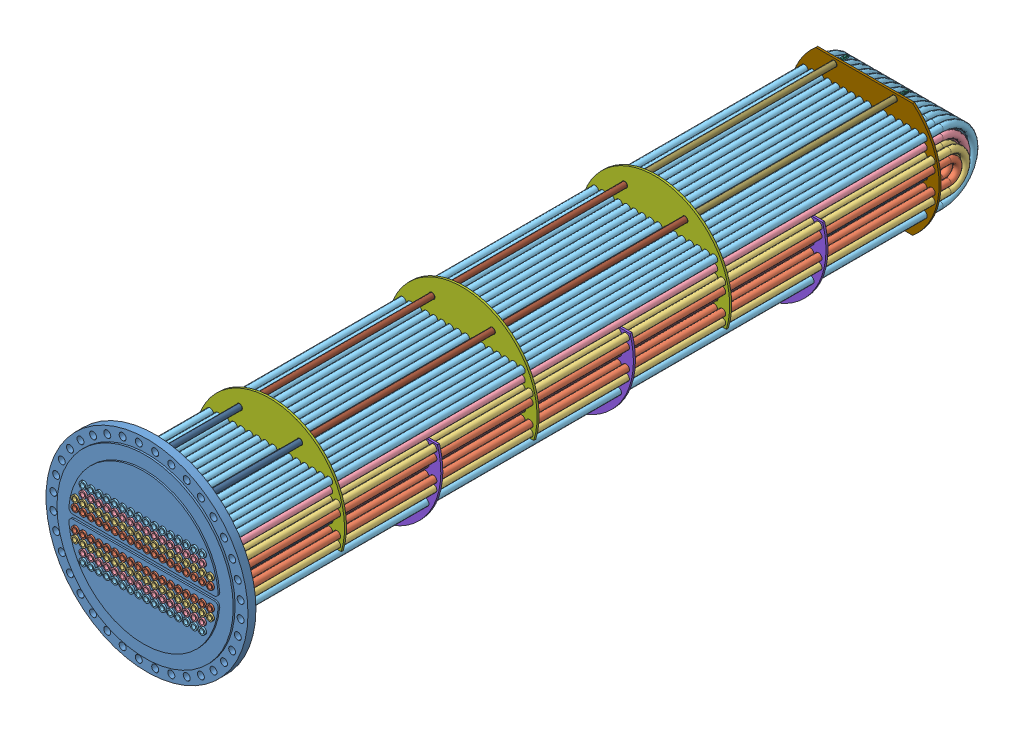
SolidWorks assembly assembly of u tube, configuration Default. Lengths in mm.
Overall size (636 636 2440.65).
118 component instances, 14 part files, 107 mates.
Components (placement in the parent):
- Tubesheet-1: Tubesheet [Default] at (254.3026 327.9932 481.92) x (-1 0 0) z (0 0 -1) size (636 636 47)
- U Tube 0.5 Inch-1: U Tube 0.5 Inch [Default] at (41.8026 327.9932 510.42) size (21.3 81.3 2365.65)
- U Tube 0.5 In x 4844 -1: U Tube 0.5 In x 4844  [Default] at (41.8026 327.9932 510.42) size (21.3 131.3 2390.65)
- U Tube 0.5 Inch-2: U Tube 0.5 Inch [Default] at (66.8026 327.9932 510.42) size (21.3 81.3 2365.65)
- U Tube 0.5 Inch-3: U Tube 0.5 Inch [Default] at (91.8026 327.9932 510.42) size (21.3 81.3 2365.65)
- U Tube 0.5 Inch-4: U Tube 0.5 Inch [Default] at (116.8026 327.9932 510.42) size (21.3 81.3 2365.65)
- U Tube 0.5 Inch-5: U Tube 0.5 Inch [Default] at (141.8026 327.9932 510.42) size (21.3 81.3 2365.65)
- U Tube 0.5 Inch-6: U Tube 0.5 Inch [Default] at (166.8026 327.9932 510.42) size (21.3 81.3 2365.65)
- U Tube 0.5 Inch-7: U Tube 0.5 Inch [Default] at (191.8026 327.9932 510.42) size (21.3 81.3 2365.65)
- U Tube 0.5 Inch-8: U Tube 0.5 Inch [Default] at (216.8026 327.9932 510.42) size (21.3 81.3 2365.65)
- U Tube 0.5 Inch-9: U Tube 0.5 Inch [Default] at (241.8026 327.9932 510.42) size (21.3 81.3 2365.65)
- U Tube 0.5 Inch-10: U Tube 0.5 Inch [Default] at (266.8026 327.9932 510.42) size (21.3 81.3 2365.65)
- U Tube 0.5 Inch-11: U Tube 0.5 Inch [Default] at (291.8026 327.9932 510.42) size (21.3 81.3 2365.65)
- U Tube 0.5 Inch-12: U Tube 0.5 Inch [Default] at (316.8026 327.9932 510.42) size (21.3 81.3 2365.65)
- U Tube 0.5 Inch-13: U Tube 0.5 Inch [Default] at (341.8026 327.9932 510.42) size (21.3 81.3 2365.65)
- U Tube 0.5 Inch-14: U Tube 0.5 Inch [Default] at (366.8026 327.9932 510.42) size (21.3 81.3 2365.65)
- U Tube 0.5 Inch-15: U Tube 0.5 Inch [Default] at (391.8026 327.9932 510.42) size (21.3 81.3 2365.65)
- U Tube 0.5 Inch-16: U Tube 0.5 Inch [Default] at (416.8026 327.9932 510.42) size (21.3 81.3 2365.65)
- U Tube 0.5 Inch-17: U Tube 0.5 Inch [Default] at (441.8026 327.9932 510.42) size (21.3 81.3 2365.65)
- U Tube 0.5 Inch-18: U Tube 0.5 Inch [Default] at (466.8026 327.9932 510.42) size (21.3 81.3 2365.65)
- U Tube 0.5 In x 4844 -2: U Tube 0.5 In x 4844  [Default] at (66.8026 327.9932 510.42) size (21.3 131.3 2390.65)
- U Tube 0.5 In x 4844 -3: U Tube 0.5 In x 4844  [Default] at (91.8026 327.9932 510.42) size (21.3 131.3 2390.65)
- U Tube 0.5 In x 4844 -4: U Tube 0.5 In x 4844  [Default] at (116.8026 327.9932 510.42) size (21.3 131.3 2390.65)
- U Tube 0.5 In x 4844 -5: U Tube 0.5 In x 4844  [Default] at (141.8026 327.9932 510.42) size (21.3 131.3 2390.65)
- U Tube 0.5 In x 4844 -6: U Tube 0.5 In x 4844  [Default] at (166.8026 327.9932 510.42) size (21.3 131.3 2390.65)
- U Tube 0.5 In x 4844 -7: U Tube 0.5 In x 4844  [Default] at (191.8026 327.9932 510.42) size (21.3 131.3 2390.65)
- U Tube 0.5 In x 4844 -8: U Tube 0.5 In x 4844  [Default] at (216.8026 327.9932 510.42) size (21.3 131.3 2390.65)
- U Tube 0.5 In x 4844 -9: U Tube 0.5 In x 4844  [Default] at (241.8026 327.9932 510.42) size (21.3 131.3 2390.65)
- U Tube 0.5 In x 4844 -10: U Tube 0.5 In x 4844  [Default] at (266.8026 327.9932 510.42) size (21.3 131.3 2390.65)
- U Tube 0.5 In x 4844 -11: U Tube 0.5 In x 4844  [Default] at (291.8026 327.9932 510.42) size (21.3 131.3 2390.65)
- U Tube 0.5 In x 4844 -12: U Tube 0.5 In x 4844  [Default] at (316.8026 327.9932 510.42) size (21.3 131.3 2390.65)
- U Tube 0.5 In x 4844 -13: U Tube 0.5 In x 4844  [Default] at (341.8026 327.9932 510.42) size (21.3 131.3 2390.65)
- U Tube 0.5 In x 4844 -14: U Tube 0.5 In x 4844  [Default] at (366.8026 327.9932 510.42) size (21.3 131.3 2390.65)
- U Tube 0.5 In x 4844 -15: U Tube 0.5 In x 4844  [Default] at (391.8026 327.9932 510.42) size (21.3 131.3 2390.65)
- U Tube 0.5 In x 4844 -16: U Tube 0.5 In x 4844  [Default] at (416.8026 327.9932 510.42) size (21.3 131.3 2390.65)
- U Tube 0.5 In x 4844 -17: U Tube 0.5 In x 4844  [Default] at (441.8026 327.9932 510.42) size (21.3 131.3 2390.65)
- U Tube 0.5 In x 4844 -18: U Tube 0.5 In x 4844  [Default] at (466.8026 327.9932 510.42) size (21.3 131.3 2390.65)
- U Tube 0.5 In x 4923 -1: U Tube 0.5 In x 4923  [Default] at (66.8026 327.9932 510.42) size (21.3 181.3 2415.65)
- U Tube 0.5 In x 5000 -1: U Tube 0.5 In x 5000  [Default] at (66.8026 327.9932 510.42) size (21.3 231.3 2440.65)
- U Tube 0.5 In x 5000 -2: U Tube 0.5 In x 5000  [Default] at (91.8026 327.9932 510.42) size (21.3 231.3 2440.65)
- U Tube 0.5 In x 5000 -3: U Tube 0.5 In x 5000  [Default] at (116.8026 327.9932 510.42) size (21.3 231.3 2440.65)
- U Tube 0.5 In x 5000 -4: U Tube 0.5 In x 5000  [Default] at (141.8026 327.9932 510.42) size (21.3 231.3 2440.65)
- U Tube 0.5 In x 5000 -5: U Tube 0.5 In x 5000  [Default] at (166.8026 327.9932 510.42) size (21.3 231.3 2440.65)
- U Tube 0.5 In x 5000 -6: U Tube 0.5 In x 5000  [Default] at (191.8026 327.9932 510.42) size (21.3 231.3 2440.65)
- U Tube 0.5 In x 5000 -7: U Tube 0.5 In x 5000  [Default] at (216.8026 327.9932 510.42) size (21.3 231.3 2440.65)
- U Tube 0.5 In x 5000 -8: U Tube 0.5 In x 5000  [Default] at (241.8026 327.9932 510.42) size (21.3 231.3 2440.65)
- U Tube 0.5 In x 5000 -9: U Tube 0.5 In x 5000  [Default] at (266.8026 327.9932 510.42) size (21.3 231.3 2440.65)
- U Tube 0.5 In x 5000 -10: U Tube 0.5 In x 5000  [Default] at (291.8026 327.9932 510.42) size (21.3 231.3 2440.65)
- U Tube 0.5 In x 5000 -11: U Tube 0.5 In x 5000  [Default] at (316.8026 327.9932 510.42) size (21.3 231.3 2440.65)
- U Tube 0.5 In x 5000 -12: U Tube 0.5 In x 5000  [Default] at (341.8026 327.9932 510.42) size (21.3 231.3 2440.65)
- U Tube 0.5 In x 5000 -13: U Tube 0.5 In x 5000  [Default] at (366.8026 327.9932 510.42) size (21.3 231.3 2440.65)
- U Tube 0.5 In x 5000 -14: U Tube 0.5 In x 5000  [Default] at (391.8026 327.9932 510.42) size (21.3 231.3 2440.65)
- U Tube 0.5 In x 5000 -15: U Tube 0.5 In x 5000  [Default] at (416.8026 327.9932 510.42) size (21.3 231.3 2440.65)
- U Tube 0.5 In x 5000 -16: U Tube 0.5 In x 5000  [Default] at (441.8026 327.9932 510.42) size (21.3 231.3 2440.65)
- U Tube 0.5 In x 4923 -2: U Tube 0.5 In x 4923  [Default] at (91.8026 327.9932 510.42) size (21.3 181.3 2415.65)
- U Tube 0.5 In x 4923 -3: U Tube 0.5 In x 4923  [Default] at (116.8026 327.9932 510.42) size (21.3 181.3 2415.65)
- U Tube 0.5 In x 4923 -4: U Tube 0.5 In x 4923  [Default] at (141.8026 327.9932 510.42) size (21.3 181.3 2415.65)
- U Tube 0.5 In x 4923 -5: U Tube 0.5 In x 4923  [Default] at (166.8026 327.9932 510.42) size (21.3 181.3 2415.65)
- U Tube 0.5 In x 4923 -6: U Tube 0.5 In x 4923  [Default] at (191.8026 327.9932 510.42) size (21.3 181.3 2415.65)
- U Tube 0.5 In x 4923 -7: U Tube 0.5 In x 4923  [Default] at (216.8026 327.9932 510.42) size (21.3 181.3 2415.65)
- U Tube 0.5 In x 4923 -8: U Tube 0.5 In x 4923  [Default] at (241.8026 327.9932 510.42) size (21.3 181.3 2415.65)
- U Tube 0.5 In x 4923 -9: U Tube 0.5 In x 4923  [Default] at (266.8026 327.9932 510.42) size (21.3 181.3 2415.65)
- U Tube 0.5 In x 4923 -10: U Tube 0.5 In x 4923  [Default] at (291.8026 327.9932 510.42) size (21.3 181.3 2415.65)
- U Tube 0.5 In x 4923 -11: U Tube 0.5 In x 4923  [Default] at (316.8026 327.9932 510.42) size (21.3 181.3 2415.65)
- U Tube 0.5 In x 4923 -12: U Tube 0.5 In x 4923  [Default] at (341.8026 327.9932 510.42) size (21.3 181.3 2415.65)
- U Tube 0.5 In x 4923 -13: U Tube 0.5 In x 4923  [Default] at (366.8026 327.9932 510.42) size (21.3 181.3 2415.65)
- U Tube 0.5 In x 4923 -14: U Tube 0.5 In x 4923  [Default] at (391.8026 327.9932 510.42) size (21.3 181.3 2415.65)
- U Tube 0.5 In x 4923 -15: U Tube 0.5 In x 4923  [Default] at (416.8026 327.9932 510.42) size (21.3 181.3 2415.65)
- U Tube 0.5 In x 4923 -16: U Tube 0.5 In x 4923  [Default] at (441.8026 327.9932 510.42) size (21.3 181.3 2415.65)
- Tie Road-1: Tie Road [Default] at (349.3026 163.4484 -666.58) size (9.99 9.59 2280.98)
- Plate spacer 2-1: Plate spacer 2 [Default] at (254.8433 328.9394 105.245) size (472 306 6.35)
- Plate spacer-1: Plate spacer [Default] at (253.7619 327.047 -197.935) x (-1 0 0) z (0 0 1) size (472 306 6.35)
- Plate spacer 2-2: Plate spacer 2 [Default] at (254.8433 328.9394 -501.105) size (472 306 6.35)
- Plate spacer 2-3: Plate spacer 2 [Default] at (254.8433 328.9394 -1107.455) size (472 306 6.35)
- Plate spacer-2: Plate spacer [Default] at (253.7619 327.047 -804.285) x (-1 0 0) z (0 0 1) size (472 306 6.35)
- Plate spacer-3: Plate spacer [Default] at (253.7619 327.047 -1410.635) x (-1 0 0) z (0 0 1) size (472 306 6.35)
- Plate Spacer 3-1: Plate Spacer 3 [Default] at (252.2845 352.0761 -1766.985) size (472 360 6.35)
- Tie Road-2: Tie Road [Default] at (159.3026 163.4484 -666.58) x (0.5 -0.866025 0) z (0 0 1) size (9.99 9.59 2280.98)
- Tie Road-3: Tie Road [Default] at (64.3026 327.9932 -666.58) x (-0.5 -0.866025 0) z (0 0 1) size (9.99 9.59 2280.98)
- Tie Road-4: Tie Road [Default] at (159.3026 492.538 -666.58) x (-1 0 0) z (0 0 1) size (9.99 9.59 2280.98)
- Tie Road-5: Tie Road [Default] at (349.3026 492.538 -666.58) x (-0.5 0.866025 0) z (0 0 1) size (9.99 9.59 2280.98)
- Tie Road-6: Tie Road [Default] at (444.3026 327.9932 -666.58) x (0.5 0.866025 0) z (0 0 1) size (9.99 9.59 2280.98)
- Spacer 2-1: Spacer 2 [Default] at (349.3026 492.538 458.42) size (17.1 17.1 350)
- Spacer 2-2: Spacer 2 [Default] at (444.3026 327.9932 458.42) x (0.987351 0.158553 0) z (0 0 1) size (17.1 17.1 350)
- Spacer 2-4: Spacer 2 [Default] at (159.3026 492.538 458.42) x (0.959125 0.282984 0) z (0 0 1) size (17.1 17.1 350)
- Spacer 2-6: Spacer 2 [Default] at (64.3026 327.9932 458.42) x (0.928571 0.371154 0) z (0 0 1) size (17.1 17.1 350)
- Spacer 2-8: Spacer 2 [Default] at (159.3026 163.4484 -1413.81) x (0.906989 0.421154 0) z (0 0 1) size (17.1 17.1 350)
- Spacer 2-10: Spacer 2 [Default] at (349.3026 163.4484 -1413.81) x (0.902849 0.429957 0) z (0 0 1) size (17.1 17.1 350)
- Spacer 2-12: Spacer 2 [Default] at (444.3026 327.9932 -1413.81) x (0.919615 0.39282 0) z (0 0 1) size (17.1 17.1 350)
- Spacer 2-14: Spacer 2 [Default] at (64.3026 327.9932 -1413.81) x (0.952324 0.305088 0) z (0 0 1) size (17.1 17.1 350)
- Spacer 3-1: Spacer 3 [Default] at (159.3026 492.538 102.07) x (0.396884 -0.917869 0) z (0 0 1) size (17.1 17.1 600)
- Spacer 3-2: Spacer 3 [Default] at (349.3026 492.538 102.07) x (0.537395 -0.843331 0) z (0 0 1) size (17.1 17.1 600)
- Spacer 3-4: Spacer 3 [Default] at (159.3026 492.538 -504.28) x (0.640403 -0.768039 0) z (0 0 1) size (17.1 17.1 600)
- Spacer 3-6: Spacer 3 [Default] at (349.3026 492.538 -504.28) x (0.709206 -0.705001 0) z (0 0 1) size (17.1 17.1 600)
- Spacer 3-8: Spacer 3 [Default] at (159.3026 163.4484 -201.11) x (0.746534 -0.665348 0) z (0 0 1) size (17.1 17.1 600)
- Spacer 3-10: Spacer 3 [Default] at (349.3026 163.4484 -201.11) x (0.752971 -0.658054 0) z (0 0 1) size (17.1 17.1 600)
- Spacer 3-12: Spacer 3 [Default] at (349.3026 163.4484 -807.46) x (0.725538 -0.688182 0) z (0 0 1) size (17.1 17.1 600)
- Spacer 3-14: Spacer 3 [Default] at (159.3026 163.4484 -807.46) x (0.657993 -0.753024 0) z (0 0 1) size (17.1 17.1 600)
- Spacer 4-1: Spacer 4 [Default] at (349.3026 163.4484 458.415) x (-0.656947 -0.753937 0) z (0 0 1) size (17.1 17.1 653.17)
- Spacer 4-2: Spacer 4 [Default] at (159.3026 163.4484 458.415) x (-0.529098 -0.848561 0) z (0 0 1) size (17.1 17.1 653.17)
- Spacer 4-4: Spacer 4 [Default] at (349.3026 492.538 -1110.635) x (-0.416742 -0.909025 0) z (0 0 1) size (17.1 17.1 653.17)
- Spacer 4-6: Spacer 4 [Default] at (159.3026 492.538 -1110.635) x (-0.330196 -0.943912 0) z (0 0 1) size (17.1 17.1 653.17)
- Spacer 1-1: Spacer 1 [Default] at (444.3026 327.9932 102.08) x (0.766722 -0.641979 0) z (0 0 1) size (17.1 17.1 296.85)
- Spacer 1-2: Spacer 1 [Default] at (444.3026 327.9932 -201.095) x (0.858811 -0.512293 0) z (0 0 1) size (17.1 17.1 296.85)
- Spacer 1-4: Spacer 1 [Default] at (444.3026 327.9932 -504.27) x (0.917052 -0.398768 0) z (0 0 1) size (17.1 17.1 296.85)
- Spacer 1-6: Spacer 1 [Default] at (444.3026 327.9932 -807.445) x (0.950229 -0.311552 0) z (0 0 1) size (17.1 17.1 296.85)
- Spacer 1-8: Spacer 1 [Default] at (444.3026 327.9932 -1110.62) x (0.965781 -0.259361 0) z (0 0 1) size (17.1 17.1 296.85)
- Spacer 1-10: Spacer 1 [Default] at (64.3026 327.9932 -1110.62) x (0.968258 -0.249953 0) z (0 0 1) size (17.1 17.1 296.85)
- Spacer 1-12: Spacer 1 [Default] at (64.3026 327.9932 -504.27) x (0.957272 -0.28919 0) z (0 0 1) size (17.1 17.1 296.85)
- Spacer 1-14: Spacer 1 [Default] at (64.3026 327.9932 -807.445) x (0.926028 -0.377455 0) z (0 0 1) size (17.1 17.1 296.85)
- Spacer 1-16: Spacer 1 [Default] at (64.3026 327.9932 -201.095) x (0.863946 -0.503584 0) z (0 0 1) size (17.1 17.1 296.85)
- Spacer 1-18: Spacer 1 [Default] at (64.3026 327.9932 102.08) x (0.932862 -0.360233 0) z (0 0 1) size (17.1 17.1 296.85)
- hex flange nut gradea_iso-1: hex flange nut gradea_iso [ISO - 4161 - M10 - N] at (159.3026 492.538 -1780.16) x (0.923728 0.383049 0) z (0 0 -1) size (21.8 21.8 10)
- hex flange nut gradea_iso-2: hex flange nut gradea_iso [ISO - 4161 - M10 - N] at (349.3026 492.538 -1780.16) x (0.923728 0.383049 0) z (0 0 -1) size (21.8 21.8 10)
- hex flange nut gradea_iso-3: hex flange nut gradea_iso [ISO - 4161 - M10 - N] at (444.2942 327.9932 -1780.16) x (0.923728 0.383049 0) z (0 0 -1) size (21.8 21.8 10)
- hex flange nut gradea_iso-4: hex flange nut gradea_iso [ISO - 4161 - M10 - N] at (349.3026 163.4484 -1780.16) x (0.923728 0.383049 0) z (0 0 -1) size (21.8 21.8 10)
- hex flange nut gradea_iso-5: hex flange nut gradea_iso [ISO - 4161 - M10 - N] at (159.3026 163.4484 -1780.16) x (0.923728 0.383049 0) z (0 0 -1) size (21.8 21.8 10)
- hex flange nut gradea_iso-6: hex flange nut gradea_iso [ISO - 4161 - M10 - N] at (65.3924 327.9932 -1780.16) x (0.923728 0.383049 0) z (0 0 -1) size (21.8 21.8 10)
Mates (geometry in assembly coordinates):
- Concentric1: concentric aligned: cylinder of Tubesheet-1 through (41.8026 357.9932 505.421) axis (0 0 -1) radius 11; cylinder of U Tube 0.5 Inch-1 through (41.8026 357.9932 510.42) axis (0 0 -1) radius 10.65
- Concentric2: concentric anti-aligned: cylinder of Tubesheet-1 through (41.8026 297.9932 505.421) axis (0 0 -1) radius 11; cylinder of U Tube 0.5 Inch-1 through (41.8026 297.9932 -1814.58) axis (0 0 1) radius 10.65
- Distance1: distance = 5 mm aligned: plane of Tubesheet-1 through (32.1568 347.4932 505.42) normal (0 0 1); plane of U Tube 0.5 Inch-1 through (41.8026 357.9932 510.42) normal (0 0 1)
- Concentric3: concentric aligned: cylinder of Tubesheet-1 through (41.8026 382.9932 505.421) axis (0 0 -1) radius 11; cylinder of U Tube 0.5 In x 4844 -1 through (41.8026 382.9932 510.42) axis (0 0 -1) radius 10.65
- Concentric4: concentric anti-aligned: cylinder of Tubesheet-1 through (41.8026 272.9932 505.421) axis (0 0 -1) radius 11; cylinder of U Tube 0.5 In x 4844 -1 through (41.8026 272.9932 -1814.58) axis (0 0 1) radius 10.65
- Distance2: distance = 5 mm aligned: plane of U Tube 0.5 In x 4844 -1 through (41.8026 382.9932 510.42) normal (0 0 1); plane of Tubesheet-1 through (32.1568 347.4932 505.42) normal (0 0 1)
- Concentric5: concentric aligned: cylinder of Tubesheet-1 through (66.8026 407.9932 505.421) axis (0 0 -1) radius 11; cylinder of U Tube 0.5 In x 4923 -1 through (66.8026 407.9932 510.42) axis (0 0 -1) radius 10.65
- Concentric6: concentric anti-aligned: cylinder of Tubesheet-1 through (66.8026 247.9932 505.421) axis (0 0 -1) radius 11; cylinder of U Tube 0.5 In x 4923 -1 through (66.8026 247.9932 -1814.58) axis (0 0 1) radius 10.65
- Distance3: distance = 5 mm aligned: plane of Tubesheet-1 through (32.1568 347.4932 505.42) normal (0 0 1); plane of U Tube 0.5 In x 4923 -1 through (66.8026 407.9932 510.42) normal (0 0 1)
- Concentric7: concentric aligned: cylinder of Tubesheet-1 through (66.8026 432.9932 505.421) axis (0 0 -1) radius 11; cylinder of U Tube 0.5 In x 5000 -1 through (66.8026 432.9932 510.42) axis (0 0 -1) radius 10.65
- Distance4: distance = 5 mm aligned: plane of Tubesheet-1 through (32.1568 347.4932 505.42) normal (0 0 1); plane of U Tube 0.5 In x 5000 -1 through (66.8026 432.9932 510.42) normal (0 0 1)
- Concentric8: concentric anti-aligned: cylinder of Tubesheet-1 through (66.8026 222.9932 505.421) axis (0 0 -1) radius 11; cylinder of U Tube 0.5 In x 5000 -1 through (66.8026 222.9932 -1814.58) axis (0 0 1) radius 10.65
- Distance5: distance = 15 mm anti-aligned: plane of Tubesheet-1 through (254.3026 327.9932 458.42) normal (0 0 -1); plane of Tie Road-1 through (349.3026 163.4484 473.42) normal (0 0 1)
- Concentric9: concentric anti-aligned: cone of Tubesheet-1 through (349.3026 163.4484 458.8063) axis (0 0 1); cylinder of Tie Road-1 through (349.3026 163.4484 473.42) axis (0 0 -1) radius 4.7625
- Concentric10: concentric aligned: cylinder of U Tube 0.5 Inch-1 through (41.8026 357.9932 510.42) axis (0 0 -1) radius 10.65; cylinder of Plate spacer 2-1 through (41.8026 357.9932 108.42) axis (0 0 -1) radius 11
- Concentric11: concentric anti-aligned: cylinder of U Tube 0.5 In x 4844 -1 through (41.8026 272.9932 -1814.58) axis (0 0 1) radius 10.65; cylinder of Plate spacer 2-1 through (41.8026 272.9932 108.42) axis (0 0 -1) radius 11
- Distance6: distance = 350 mm anti-aligned: plane of Tubesheet-1 through (32.1568 347.4932 458.42) normal (0 0 -1); plane of Plate spacer 2-1 through (254.8433 328.9394 108.42) normal (0 0 1)
- Concentric12: concentric aligned: cylinder of U Tube 0.5 In x 4844 -1 through (41.8026 382.9932 510.42) axis (0 0 -1) radius 10.65; cylinder of Plate spacer-1 through (41.8026 382.9932 -194.76) axis (0 0 -1) radius 11
- Concentric13: concentric aligned: cylinder of U Tube 0.5 Inch-1 through (41.8026 357.9932 510.42) axis (0 0 -1) radius 10.65; cylinder of Plate spacer-1 through (41.8026 357.9932 -194.76) axis (0 0 -1) radius 11
- Distance7: distance = 653.18 mm anti-aligned: plane of Tubesheet-1 through (32.1568 347.4932 458.42) normal (0 0 -1); plane of Plate spacer-1 through (253.7619 327.047 -194.76) normal (0 0 1)
- Distance8: distance = 600 mm anti-aligned: plane of Plate spacer 2-1 through (254.8433 328.9394 102.07) normal (0 0 -1); plane of Plate spacer 2-2 through (254.8433 328.9394 -497.93) normal (0 0 1)
- Concentric14: concentric aligned: cylinder of U Tube 0.5 Inch-1 through (41.8026 357.9932 510.42) axis (0 0 -1) radius 10.65; cylinder of Plate spacer 2-2 through (41.8026 357.9932 -497.93) axis (0 0 -1) radius 11
- Concentric15: concentric aligned: cylinder of U Tube 0.5 In x 4844 -1 through (41.8026 382.9932 510.42) axis (0 0 -1) radius 10.65; cylinder of Plate spacer 2-2 through (41.8026 382.9932 -497.93) axis (0 0 -1) radius 11
- Distance9: distance = 600 mm anti-aligned: plane of Plate spacer 2-2 through (254.8433 328.9394 -504.28) normal (0 0 -1); plane of Plate spacer 2-3 through (254.8433 328.9394 -1104.28) normal (0 0 1)
- Concentric16: concentric aligned: cylinder of U Tube 0.5 Inch-1 through (41.8026 357.9932 510.42) axis (0 0 -1) radius 10.65; cylinder of Plate spacer 2-3 through (41.8026 357.9932 -1104.28) axis (0 0 -1) radius 11
- Concentric17: concentric aligned: cylinder of U Tube 0.5 In x 4844 -1 through (41.8026 382.9932 510.42) axis (0 0 -1) radius 10.65; cylinder of Plate spacer 2-3 through (41.8026 382.9932 -1104.28) axis (0 0 -1) radius 11
- Distance10: distance = 600 mm anti-aligned: plane of Plate spacer-1 through (253.7619 327.047 -201.11) normal (0 0 -1); plane of Plate spacer-2 through (253.7619 327.047 -801.11) normal (0 0 1)
- Concentric18: concentric aligned: cylinder of U Tube 0.5 Inch-1 through (41.8026 357.9932 510.42) axis (0 0 -1) radius 10.65; cylinder of Plate spacer-2 through (41.8026 357.9932 -801.11) axis (0 0 -1) radius 11
- Concentric19: concentric aligned: cylinder of U Tube 0.5 In x 4844 -1 through (41.8026 382.9932 510.42) axis (0 0 -1) radius 10.65; cylinder of Plate spacer-2 through (41.8026 382.9932 -801.11) axis (0 0 -1) radius 11
- Distance11: distance = 600 mm anti-aligned: plane of Plate spacer-2 through (253.7619 327.047 -807.46) normal (0 0 -1); plane of Plate spacer-3 through (253.7619 327.047 -1407.46) normal (0 0 1)
- Concentric20: concentric aligned: cylinder of U Tube 0.5 Inch-1 through (41.8026 357.9932 510.42) axis (0 0 -1) radius 10.65; cylinder of Plate spacer-3 through (41.8026 357.9932 -1407.46) axis (0 0 -1) radius 11
- Concentric21: concentric aligned: cylinder of U Tube 0.5 In x 4844 -1 through (41.8026 382.9932 510.42) axis (0 0 -1) radius 10.65; cylinder of Plate spacer-3 through (41.8026 382.9932 -1407.46) axis (0 0 -1) radius 11
- Distance12: distance = 350 mm anti-aligned: plane of Plate Spacer 3-1 through (252.2845 352.0761 -1763.81) normal (0 0 1); plane of Plate spacer-3 through (253.7619 327.047 -1413.81) normal (0 0 -1)
- Concentric22: concentric aligned: cylinder of U Tube 0.5 Inch-1 through (41.8026 357.9932 510.42) axis (0 0 -1) radius 10.65; cylinder of Plate Spacer 3-1 through (41.8026 357.9932 -1763.81) axis (0 0 -1) radius 11
- Concentric23: concentric aligned: cylinder of U Tube 0.5 In x 4844 -1 through (41.8026 382.9932 510.42) axis (0 0 -1) radius 10.65; cylinder of Plate Spacer 3-1 through (41.8026 382.9932 -1763.81) axis (0 0 -1) radius 11
- Concentric24: concentric anti-aligned: cylinder of Tie Road-5 through (349.3026 492.538 473.42) axis (0 0 -1) radius 4.7625; cylinder of Spacer 2-1 through (349.3026 492.538 108.42) axis (0 0 1) radius 5.35
- Width1: width anti-aligned: plane of Plate spacer 2-1 through (254.8433 328.9394 108.42) normal (0 0 1); plane of Tubesheet-1 through (32.1568 347.4932 458.42) normal (0 0 -1); plane of Spacer 2-1 through (349.3026 492.538 108.42) normal (0 0 -1); plane of Spacer 2-1 through (349.3026 492.538 458.42) normal (0 0 1)
- Concentric25: concentric anti-aligned: cylinder of Tie Road-6 through (444.3026 327.9932 473.42) axis (0 0 -1) radius 4.7625; cylinder of Spacer 2-2 through (444.3026 327.9932 108.42) axis (0 0 1) radius 5.35
- Width2: width anti-aligned: plane of Plate spacer 2-1 through (254.8433 328.9394 108.42) normal (0 0 1); plane of Tubesheet-1 through (32.1568 347.4932 458.42) normal (0 0 -1); plane of Spacer 2-2 through (444.3026 327.9932 108.42) normal (0 0 -1); plane of Spacer 2-2 through (444.3026 327.9932 458.42) normal (0 0 1)
- Concentric26: concentric anti-aligned: cylinder of Tie Road-4 through (159.3026 492.538 473.42) axis (0 0 -1) radius 4.7625; cylinder of Spacer 2-4 through (159.3026 492.538 108.42) axis (0 0 1) radius 5.35
- Width3: width anti-aligned: plane of Plate spacer 2-1 through (254.8433 328.9394 108.42) normal (0 0 1); plane of Tubesheet-1 through (32.1568 347.4932 458.42) normal (0 0 -1); plane of Spacer 2-4 through (159.3026 492.538 108.42) normal (0 0 -1); plane of Spacer 2-4 through (159.3026 492.538 458.42) normal (0 0 1)
- Concentric27: concentric anti-aligned: cylinder of Tie Road-3 through (64.3026 327.9932 473.42) axis (0 0 -1) radius 4.7625; cylinder of Spacer 2-6 through (64.3026 327.9932 108.42) axis (0 0 1) radius 5.35
- Width4: width anti-aligned: plane of Tubesheet-1 through (32.1568 347.4932 458.42) normal (0 0 -1); plane of Plate spacer 2-1 through (254.8433 328.9394 108.42) normal (0 0 1); plane of Spacer 2-6 through (64.3026 327.9932 108.42) normal (0 0 -1); plane of Spacer 2-6 through (64.3026 327.9932 458.42) normal (0 0 1)
- Concentric28: concentric anti-aligned: cylinder of Tie Road-2 through (159.3026 163.4484 473.42) axis (0 0 -1) radius 4.7625; cylinder of Spacer 2-8 through (159.3026 163.4484 -1763.81) axis (0 0 1) radius 5.35
- Width5: width anti-aligned: plane of Plate spacer-3 through (253.7619 327.047 -1413.81) normal (0 0 -1); plane of Plate Spacer 3-1 through (252.2845 352.0761 -1763.81) normal (0 0 1); plane of Spacer 2-8 through (159.3026 163.4484 -1763.81) normal (0 0 -1); plane of Spacer 2-8 through (159.3026 163.4484 -1413.81) normal (0 0 1)
- Concentric29: concentric anti-aligned: cylinder of Tie Road-1 through (349.3026 163.4484 473.42) axis (0 0 -1) radius 4.7625; cylinder of Spacer 2-10 through (349.3026 163.4484 -1763.81) axis (0 0 1) radius 5.35
- Width6: width anti-aligned: plane of Plate Spacer 3-1 through (252.2845 352.0761 -1763.81) normal (0 0 1); plane of Plate spacer-3 through (253.7619 327.047 -1413.81) normal (0 0 -1); plane of Spacer 2-10 through (349.3026 163.4484 -1763.81) normal (0 0 -1); plane of Spacer 2-10 through (349.3026 163.4484 -1413.81) normal (0 0 1)
- Concentric30: concentric anti-aligned: cylinder of Tie Road-6 through (444.3026 327.9932 473.42) axis (0 0 -1) radius 4.7625; cylinder of Spacer 2-12 through (444.3026 327.9932 -1763.81) axis (0 0 1) radius 5.35
- Width7: width anti-aligned: plane of Plate Spacer 3-1 through (252.2845 352.0761 -1763.81) normal (0 0 1); plane of Plate spacer-3 through (253.7619 327.047 -1413.81) normal (0 0 -1); plane of Spacer 2-12 through (444.3026 327.9932 -1763.81) normal (0 0 -1); plane of Spacer 2-12 through (444.3026 327.9932 -1413.81) normal (0 0 1)
- Concentric31: concentric anti-aligned: cylinder of Tie Road-3 through (64.3026 327.9932 473.42) axis (0 0 -1) radius 4.7625; cylinder of Spacer 2-14 through (64.3026 327.9932 -1763.81) axis (0 0 1) radius 5.35
- Width8: width anti-aligned: plane of Plate Spacer 3-1 through (252.2845 352.0761 -1763.81) normal (0 0 1); plane of Plate spacer-3 through (253.7619 327.047 -1413.81) normal (0 0 -1); plane of Spacer 2-14 through (64.3026 327.9932 -1763.81) normal (0 0 -1); plane of Spacer 2-14 through (64.3026 327.9932 -1413.81) normal (0 0 1)
- Concentric32: concentric anti-aligned: cylinder of Tie Road-4 through (159.3026 492.538 473.42) axis (0 0 -1) radius 4.7625; cylinder of Spacer 3-1 through (159.3026 492.538 -497.93) axis (0 0 1) radius 5.35
- Width9: width anti-aligned: plane of Spacer 3-1 through (159.3026 492.538 102.07) normal (0 0 1); plane of Spacer 3-1 through (159.3026 492.538 -497.93) normal (0 0 -1); plane of Plate spacer 2-1 through (254.8433 328.9394 102.07) normal (0 0 -1); plane of Plate spacer 2-2 through (254.8433 328.9394 -497.93) normal (0 0 1)
- Concentric33: concentric anti-aligned: cylinder of Tie Road-5 through (349.3026 492.538 473.42) axis (0 0 -1) radius 4.7625; cylinder of Spacer 3-2 through (349.3026 492.538 -497.93) axis (0 0 1) radius 5.35
- Width10: width anti-aligned: plane of Spacer 3-2 through (349.3026 492.538 102.07) normal (0 0 1); plane of Spacer 3-2 through (349.3026 492.538 -497.93) normal (0 0 -1); plane of Plate spacer 2-2 through (254.8433 328.9394 -497.93) normal (0 0 1); plane of Plate spacer 2-1 through (254.8433 328.9394 102.07) normal (0 0 -1)
- Concentric34: concentric anti-aligned: cylinder of Tie Road-4 through (159.3026 492.538 473.42) axis (0 0 -1) radius 4.7625; cylinder of Spacer 3-4 through (159.3026 492.538 -1104.28) axis (0 0 1) radius 5.35
- Width11: width anti-aligned: plane of Spacer 3-4 through (159.3026 492.538 -504.28) normal (0 0 1); plane of Spacer 3-4 through (159.3026 492.538 -1104.28) normal (0 0 -1); plane of Plate spacer 2-3 through (254.8433 328.9394 -1104.28) normal (0 0 1); plane of Plate spacer 2-2 through (254.8433 328.9394 -504.28) normal (0 0 -1)
- Concentric35: concentric anti-aligned: cylinder of Tie Road-5 through (349.3026 492.538 473.42) axis (0 0 -1) radius 4.7625; cylinder of Spacer 3-6 through (349.3026 492.538 -1104.28) axis (0 0 1) radius 5.35
- Width12: width anti-aligned: plane of Spacer 3-6 through (349.3026 492.538 -504.28) normal (0 0 1); plane of Spacer 3-6 through (349.3026 492.538 -1104.28) normal (0 0 -1); plane of Plate spacer 2-2 through (254.8433 328.9394 -504.28) normal (0 0 -1); plane of Plate spacer 2-3 through (254.8433 328.9394 -1104.28) normal (0 0 1)
- Concentric36: concentric anti-aligned: cylinder of Tie Road-2 through (159.3026 163.4484 473.42) axis (0 0 -1) radius 4.7625; cylinder of Spacer 3-8 through (159.3026 163.4484 -801.11) axis (0 0 1) radius 5.35
- Width13: width anti-aligned: plane of Spacer 3-8 through (159.3026 163.4484 -201.11) normal (0 0 1); plane of Spacer 3-8 through (159.3026 163.4484 -801.11) normal (0 0 -1); plane of Plate spacer-2 through (253.7619 327.047 -801.11) normal (0 0 1); plane of Plate spacer-1 through (253.7619 327.047 -201.11) normal (0 0 -1)
- Concentric37: concentric anti-aligned: cylinder of Tie Road-1 through (349.3026 163.4484 473.42) axis (0 0 -1) radius 4.7625; cylinder of Spacer 3-10 through (349.3026 163.4484 -801.11) axis (0 0 1) radius 5.35
- Width14: width anti-aligned: plane of Spacer 3-10 through (349.3026 163.4484 -201.11) normal (0 0 1); plane of Spacer 3-10 through (349.3026 163.4484 -801.11) normal (0 0 -1); plane of Plate spacer-1 through (253.7619 327.047 -201.11) normal (0 0 -1); plane of Plate spacer-2 through (253.7619 327.047 -801.11) normal (0 0 1)
- Concentric38: concentric anti-aligned: cylinder of Tie Road-1 through (349.3026 163.4484 473.42) axis (0 0 -1) radius 4.7625; cylinder of Spacer 3-12 through (349.3026 163.4484 -1407.46) axis (0 0 1) radius 5.35
- Width15: width anti-aligned: plane of Spacer 3-12 through (349.3026 163.4484 -807.46) normal (0 0 1); plane of Spacer 3-12 through (349.3026 163.4484 -1407.46) normal (0 0 -1); plane of Plate spacer-3 through (253.7619 327.047 -1407.46) normal (0 0 1); plane of Plate spacer-2 through (253.7619 327.047 -807.46) normal (0 0 -1)
- Concentric39: concentric anti-aligned: cylinder of Tie Road-2 through (159.3026 163.4484 473.42) axis (0 0 -1) radius 4.7625; cylinder of Spacer 3-14 through (159.3026 163.4484 -1407.46) axis (0 0 1) radius 5.35
- Width16: width anti-aligned: plane of Spacer 3-14 through (159.3026 163.4484 -807.46) normal (0 0 1); plane of Spacer 3-14 through (159.3026 163.4484 -1407.46) normal (0 0 -1); plane of Plate spacer-3 through (253.7619 327.047 -1407.46) normal (0 0 1); plane of Plate spacer-2 through (253.7619 327.047 -807.46) normal (0 0 -1)
- Concentric40: concentric anti-aligned: cylinder of Tie Road-1 through (349.3026 163.4484 473.42) axis (0 0 -1) radius 4.7625; cylinder of Spacer 4-1 through (349.3026 163.4484 -194.755) axis (0 0 1) radius 8.55
- Width17: width anti-aligned: plane of Plate spacer-1 through (253.7619 327.047 -194.76) normal (0 0 1); plane of Tubesheet-1 through (254.3026 327.9932 458.42) normal (0 0 -1); plane of Spacer 4-1 through (349.3026 163.4484 -194.755) normal (0 0 -1); plane of Spacer 4-1 through (349.3026 163.4484 458.415) normal (0 0 1)
- Concentric41: concentric anti-aligned: cylinder of Tie Road-2 through (159.3026 163.4484 473.42) axis (0 0 -1) radius 4.7625; cylinder of Spacer 4-2 through (159.3026 163.4484 -194.755) axis (0 0 1) radius 8.55
- Width18: width anti-aligned: plane of Tubesheet-1 through (254.3026 327.9932 458.42) normal (0 0 -1); plane of Plate spacer-1 through (253.7619 327.047 -194.76) normal (0 0 1); plane of Spacer 4-2 through (159.3026 163.4484 -194.755) normal (0 0 -1); plane of Spacer 4-2 through (159.3026 163.4484 458.415) normal (0 0 1)
- Concentric42: concentric anti-aligned: cylinder of Tie Road-5 through (349.3026 492.538 473.42) axis (0 0 -1) radius 4.7625; cylinder of Spacer 4-4 through (349.3026 492.538 -1763.805) axis (0 0 1) radius 8.55
- Width19: width anti-aligned: plane of Plate Spacer 3-1 through (252.2845 352.0761 -1763.81) normal (0 0 1); plane of Plate spacer 2-3 through (254.8433 328.9394 -1110.63) normal (0 0 -1); plane of Spacer 4-4 through (349.3026 492.538 -1763.805) normal (0 0 -1); plane of Spacer 4-4 through (349.3026 492.538 -1110.635) normal (0 0 1)
- Concentric43: concentric anti-aligned: cylinder of Tie Road-4 through (159.3026 492.538 473.42) axis (0 0 -1) radius 4.7625; cylinder of Spacer 4-6 through (159.3026 492.538 -1763.805) axis (0 0 1) radius 8.55
- Width20: width anti-aligned: plane of Plate spacer 2-3 through (254.8433 328.9394 -1110.63) normal (0 0 -1); plane of Plate Spacer 3-1 through (252.2845 352.0761 -1763.81) normal (0 0 1); plane of Spacer 4-6 through (159.3026 492.538 -1763.805) normal (0 0 -1); plane of Spacer 4-6 through (159.3026 492.538 -1110.635) normal (0 0 1)
- Concentric44: concentric anti-aligned: cylinder of Tie Road-6 through (444.3026 327.9932 473.42) axis (0 0 -1) radius 4.7625; cylinder of Spacer 1-1 through (444.3026 327.9932 -194.77) axis (0 0 1) radius 8.55
- Width21: width anti-aligned: plane of Spacer 1-1 through (444.3026 327.9932 -194.77) normal (0 0 -1); plane of Spacer 1-1 through (444.3026 327.9932 102.08) normal (0 0 1); plane of Plate spacer-1 through (253.7619 327.047 -194.76) normal (0 0 1); plane of Plate spacer 2-1 through (254.8433 328.9394 102.07) normal (0 0 -1)
- Concentric45: concentric anti-aligned: cylinder of Tie Road-6 through (444.3026 327.9932 473.42) axis (0 0 -1) radius 4.7625; cylinder of Spacer 1-2 through (444.3026 327.9932 -497.945) axis (0 0 1) radius 8.55
- Width22: width anti-aligned: plane of Spacer 1-2 through (444.3026 327.9932 -497.945) normal (0 0 -1); plane of Spacer 1-2 through (444.3026 327.9932 -201.095) normal (0 0 1); plane of Plate spacer 2-2 through (254.8433 328.9394 -497.93) normal (0 0 1); plane of Plate spacer-1 through (253.7619 327.047 -201.11) normal (0 0 -1)
- Concentric46: concentric anti-aligned: cylinder of Tie Road-6 through (444.3026 327.9932 473.42) axis (0 0 -1) radius 4.7625; cylinder of Spacer 1-4 through (444.3026 327.9932 -801.12) axis (0 0 1) radius 8.55
- Width23: width anti-aligned: plane of Spacer 1-4 through (444.3026 327.9932 -801.12) normal (0 0 -1); plane of Spacer 1-4 through (444.3026 327.9932 -504.27) normal (0 0 1); plane of Plate spacer-2 through (253.7619 327.047 -801.11) normal (0 0 1); plane of Plate spacer 2-2 through (254.8433 328.9394 -504.28) normal (0 0 -1)
- Concentric47: concentric anti-aligned: cylinder of Tie Road-6 through (444.3026 327.9932 473.42) axis (0 0 -1) radius 4.7625; cylinder of Spacer 1-6 through (444.3026 327.9932 -1104.295) axis (0 0 1) radius 8.55
- Width24: width anti-aligned: plane of Spacer 1-6 through (444.3026 327.9932 -1104.295) normal (0 0 -1); plane of Spacer 1-6 through (444.3026 327.9932 -807.445) normal (0 0 1); plane of Plate spacer-2 through (253.7619 327.047 -807.46) normal (0 0 -1); plane of Plate spacer 2-3 through (254.8433 328.9394 -1104.28) normal (0 0 1)
- Concentric48: concentric anti-aligned: cylinder of Tie Road-6 through (444.3026 327.9932 473.42) axis (0 0 -1) radius 4.7625; cylinder of Spacer 1-8 through (444.3026 327.9932 -1407.47) axis (0 0 1) radius 8.55
- Width25: width anti-aligned: plane of Spacer 1-8 through (444.3026 327.9932 -1407.47) normal (0 0 -1); plane of Spacer 1-8 through (444.3026 327.9932 -1110.62) normal (0 0 1); plane of Plate spacer-3 through (253.7619 327.047 -1407.46) normal (0 0 1); plane of Plate spacer 2-3 through (254.8433 328.9394 -1110.63) normal (0 0 -1)
- Concentric49: concentric anti-aligned: cylinder of Tie Road-3 through (64.3026 327.9932 473.42) axis (0 0 -1) radius 4.7625; cylinder of Spacer 1-10 through (64.3026 327.9932 -1407.47) axis (0 0 1) radius 8.55
- Width26: width anti-aligned: plane of Spacer 1-10 through (64.3026 327.9932 -1407.47) normal (0 0 -1); plane of Spacer 1-10 through (64.3026 327.9932 -1110.62) normal (0 0 1); plane of Plate spacer 2-3 through (254.8433 328.9394 -1110.63) normal (0 0 -1); plane of Plate spacer-3 through (253.7619 327.047 -1407.46) normal (0 0 1)
- Concentric51: concentric anti-aligned: cylinder of Tie Road-3 through (64.3026 327.9932 473.42) axis (0 0 -1) radius 4.7625; cylinder of Spacer 1-12 through (64.3026 327.9932 -801.12) axis (0 0 1) radius 8.55
- Width28: width anti-aligned: plane of Spacer 1-12 through (64.3026 327.9932 -801.12) normal (0 0 -1); plane of Spacer 1-12 through (64.3026 327.9932 -504.27) normal (0 0 1); plane of Plate spacer-2 through (253.7619 327.047 -801.11) normal (0 0 1); plane of Plate spacer 2-2 through (254.8433 328.9394 -504.28) normal (0 0 -1)
- Concentric52: concentric anti-aligned: cylinder of Tie Road-3 through (64.3026 327.9932 473.42) axis (0 0 -1) radius 4.7625; cylinder of Spacer 1-14 through (64.3026 327.9932 -1104.295) axis (0 0 1) radius 8.55
- Width29: width anti-aligned: plane of Spacer 1-14 through (64.3026 327.9932 -1104.295) normal (0 0 -1); plane of Spacer 1-14 through (64.3026 327.9932 -807.445) normal (0 0 1); plane of Plate spacer-2 through (253.7619 327.047 -807.46) normal (0 0 -1); plane of Plate spacer 2-3 through (254.8433 328.9394 -1104.28) normal (0 0 1)
- Concentric53: concentric anti-aligned: cylinder of Tie Road-3 through (64.3026 327.9932 473.42) axis (0 0 -1) radius 4.7625; cylinder of Spacer 1-16 through (64.3026 327.9932 -497.945) axis (0 0 1) radius 8.55
- Width30: width anti-aligned: plane of Spacer 1-16 through (64.3026 327.9932 -497.945) normal (0 0 -1); plane of Spacer 1-16 through (64.3026 327.9932 -201.095) normal (0 0 1); plane of Plate spacer 2-2 through (254.8433 328.9394 -497.93) normal (0 0 1); plane of Plate spacer-1 through (253.7619 327.047 -201.11) normal (0 0 -1)
- Concentric54: concentric anti-aligned: cylinder of Tie Road-3 through (64.3026 327.9932 473.42) axis (0 0 -1) radius 4.7625; cylinder of Spacer 1-18 through (64.3026 327.9932 -194.77) axis (0 0 1) radius 8.55
- Width31: width anti-aligned: plane of Spacer 1-18 through (64.3026 327.9932 -194.77) normal (0 0 -1); plane of Spacer 1-18 through (64.3026 327.9932 102.08) normal (0 0 1); plane of Plate spacer 2-1 through (254.8433 328.9394 102.07) normal (0 0 -1); plane of Plate spacer-1 through (253.7619 327.047 -194.76) normal (0 0 1)
- Concentric55: concentric aligned: cylinder of Plate Spacer 3-1 through (159.3026 492.538 -1763.81) axis (0 0 -1) radius 9.398; cylinder of hex flange nut gradea_iso-1 through (159.3026 492.538 -1755.1225) axis (0 0 -1) radius 5
- Coincident3: coincident anti-aligned: plane of Plate Spacer 3-1 through (252.2845 352.0761 -1770.16) normal (0 0 -1); plane of hex flange nut gradea_iso-1 through (162.6199 484.5383 -1770.16) normal (0 0 1)
- Concentric56: concentric aligned: cylinder of Plate Spacer 3-1 through (349.3026 492.538 -1763.81) axis (0 0 -1) radius 9.398; cylinder of hex flange nut gradea_iso-2 through (349.3026 492.538 -1755.1225) axis (0 0 -1) radius 5
- Coincident4: coincident anti-aligned: plane of Plate Spacer 3-1 through (252.2845 352.0761 -1770.16) normal (0 0 -1); plane of hex flange nut gradea_iso-2 through (352.6199 484.5383 -1770.16) normal (0 0 1)
- Concentric57: concentric aligned: cylinder of Plate Spacer 3-1 through (444.2942 327.9932 -1763.81) axis (0 0 -1) radius 9.398; cylinder of hex flange nut gradea_iso-3 through (444.2942 327.9932 -1755.1225) axis (0 0 -1) radius 5
- Coincident5: coincident anti-aligned: plane of Plate Spacer 3-1 through (252.2845 352.0761 -1770.16) normal (0 0 -1); plane of hex flange nut gradea_iso-3 through (447.6115 319.9935 -1770.16) normal (0 0 1)
- Concentric58: concentric aligned: cylinder of Plate Spacer 3-1 through (349.3026 163.4484 -1763.81) axis (0 0 -1) radius 9.398; cylinder of hex flange nut gradea_iso-4 through (349.3026 163.4484 -1755.1225) axis (0 0 -1) radius 5
- Coincident6: coincident anti-aligned: plane of Plate Spacer 3-1 through (252.2845 352.0761 -1770.16) normal (0 0 -1); plane of hex flange nut gradea_iso-4 through (352.6199 155.4487 -1770.16) normal (0 0 1)
- Concentric59: concentric aligned: cylinder of Plate Spacer 3-1 through (159.3026 163.4484 -1763.81) axis (0 0 -1) radius 9.398; cylinder of hex flange nut gradea_iso-5 through (159.3026 163.4484 -1755.1225) axis (0 0 -1) radius 5
- Coincident7: coincident anti-aligned: plane of Plate Spacer 3-1 through (252.2845 352.0761 -1770.16) normal (0 0 -1); plane of hex flange nut gradea_iso-5 through (162.6199 155.4487 -1770.16) normal (0 0 1)
- Concentric60: concentric aligned: cylinder of Plate Spacer 3-1 through (65.3924 327.9932 -1763.81) axis (0 0 -1) radius 9.398; cylinder of hex flange nut gradea_iso-6 through (65.3924 327.9932 -1755.1225) axis (0 0 -1) radius 5
- Coincident8: coincident anti-aligned: plane of Plate Spacer 3-1 through (252.2845 352.0761 -1770.16) normal (0 0 -1); plane of hex flange nut gradea_iso-6 through (68.7097 319.9935 -1770.16) normal (0 0 1)
